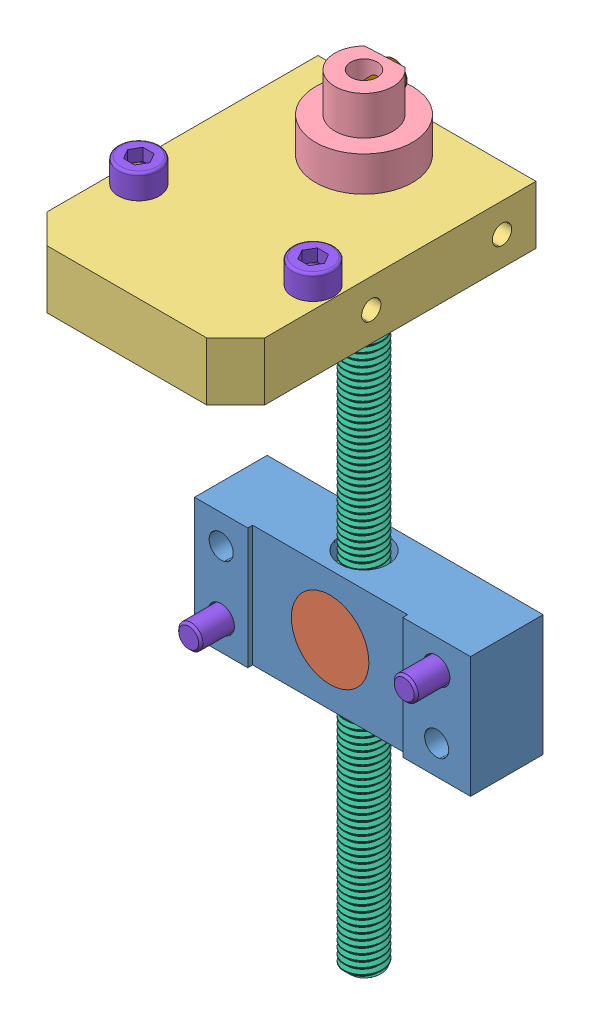
SolidWorks assembly S5 - thanh_phan, configuration Default. Lengths in mm.
Overall size (57 160.05 62).
12 component instances, 9 part files, 24 mates.
Components (placement in the parent):
- thanh ngang-5: thanh ngang [Default] at (73.0889 155.42 65.6963) x (-1 0 0) z (0 1 0) size (57 15 25)
- dai oc-1: dai oc [Default] at (71.5889 158.42 65.6963) x (0 1 0) z (1 0 0) size (16 14 16)
- tam de nho-4: tam de nho [Default] at (71.5889 241.6685 90.6963) x (1 0 0) z (0 0 -1) size (45 12 62)
- dau kep truc vit-2: dau kep truc vit [Default] at (71.5889 256.8685 72.6963) x (-0.045414 0 -0.998968) z (-0.998968 0 0.045414) size (20 25 20)
- vong_dem-2: vong_dem [Default] at (71.5889 229.8685 72.6963) x (0.969315 0 0.245821) z (-0.245821 0 0.969315) size (19.6 2 19.6)
- vit me M8x150mm-2: vit me M8x150mm [Default] at (71.5889 171.8685 72.6963) x (0.826851 0 0.562421) z (0 1 0) size (10.85 10.06 150.11)
- hex nut gradec_din-2: hex nut gradec_din [Hexagon Nut ISO 4034 - M8 - N] at (71.5889 221.9685 72.6963) x (-0.899635 0 -0.436642) z (0 -1 0) size (13 15.01 7.9)
- socket head cap screw_din-3: socket head cap screw_din [DIN 912 M5 x 16 --- 16N] at (50.0889 151.92 66.3963) x (0 0 1) z (-1 0 0) size (21 8.5 8.5)
- socket head cap screw_din-4: socket head cap screw_din [DIN 912 M5 x 16 --- 16N] at (94.5889 164.92 66.3963) x (0 0 1) z (-1 0 0) size (21 8.5 8.5)
- socket head cap screw_din-15: socket head cap screw_din [DIN 912 M5 x 12 --- 12N] at (53.5889 246.6685 101.1963) x (0 -1 0) z (0 0 1) size (17 8.5 8.5)
- socket head cap screw_din-16: socket head cap screw_din [DIN 912 M5 x 12 --- 12N] at (89.5889 246.6685 101.1963) x (0 -1 0) z (0 0 1) size (17 8.5 8.5)
- socket head thin cap screw_din-18: socket head thin cap screw_din [DIN 7984 - M3 x 5 --- 3.5N] at (71.2937 252.8685 66.203) x (0.045414 0 0.998968) z (0.400979 0.915906 -0.018229) size (7 5.5 5.5)
Mates (geometry in assembly coordinates):
- Parallel48: parallel anti-aligned: plane of thanh ngang-5 through (73.0889 155.42 65.6963) normal (0 0 -1); plane of dai oc-1 through (80.1238 179.42 79.6963) normal (0 0 1)
- Concentric30: concentric anti-aligned: cylinder of thanh ngang-5 through (71.5889 -0.08 72.6963) axis (0 1 0) radius 5; cylinder of dai oc-1 through (71.5889 179.42 72.6963) axis (0 -1 0) radius 4
- Concentric31: concentric aligned: cylinder of thanh ngang-5 through (71.5889 158.42 236.6963) axis (0 0 -1) radius 8; cylinder of dai oc-1 through (71.5889 158.42 79.6963) axis (0 0 -1) radius 8
- Parallel55: parallel anti-aligned: plane of tam de nho-4 through (71.5889 241.6685 90.6963) normal (0 1 0); plane of dau kep truc vit-2 through (71.5889 231.8685 72.6963) normal (0 -1 0)
- Concentric33: concentric aligned: cylinder of tam de nho-4 through (71.5889 241.6685 72.6963) axis (0 -1 0) radius 7; cylinder of dau kep truc vit-2 through (71.5889 241.6685 72.6963) axis (0 -1 0) radius 7
- Coincident46: coincident anti-aligned: plane of tam de nho-4 through (71.5889 241.6685 90.6963) normal (0 1 0); plane of dau kep truc vit-2 through (71.5889 241.6685 72.6963) normal (0 -1 0)
- Concentric34: concentric aligned: cylinder of dau kep truc vit-2 through (71.5889 246.8685 72.6963) axis (0 -1 0) radius 4; cylinder of vong_dem-2 through (71.5889 231.8685 72.6963) axis (0 -1 0) radius 4.25
- Coincident47: coincident anti-aligned: plane of dau kep truc vit-2 through (71.5889 231.8685 72.6963) normal (0 -1 0); plane of vong_dem-2 through (71.5889 231.8685 72.6963) normal (0 1 0)
- Concentric35: concentric anti-aligned: cylinder of dau kep truc vit-2 through (71.5889 246.8685 72.6963) axis (0 -1 0) radius 4; cylinder of vit me M8x150mm-2 through (71.5889 171.8685 72.6963) axis (0 1 0) radius 3.933
- Coincident48: coincident anti-aligned: plane of dau kep truc vit-2 through (71.5889 246.8685 72.6963) normal (0 -1 0); plane of vit me M8x150mm-2 through (71.5889 246.8685 72.6963) normal (0 1 0)
- Concentric37: concentric anti-aligned: cylinder of vit me M8x150mm-2 through (71.5889 171.8685 72.6963) axis (0 1 0) radius 3.933; cylinder of hex nut gradec_din-2 through (71.5889 229.8685 72.6963) axis (0 -1 0) radius 3.4
- Coincident49: coincident anti-aligned: plane of vong_dem-2 through (71.5889 229.8685 72.6963) normal (0 -1 0); plane of hex nut gradec_din-2 through (74.8661 229.8685 65.944) normal (0 1 0)
- Lock1: lock: unknown of vit me M8x150mm-2; unknown of hex nut gradec_din-2
- Lock2: lock: unknown of dau kep truc vit-2; unknown of hex nut gradec_din-2
- Concentric62: concentric aligned: cylinder of thanh ngang-5 through (50.0889 151.92 71.3963) axis (0 0 -1) radius 5; cylinder of socket head cap screw_din-3 through (50.0889 151.92 34.6463) axis (0 0 -1) radius 4.25
- Coincident67: coincident anti-aligned: plane of thanh ngang-5 through (50.0889 151.92 71.3963) normal (0 0 -1); plane of socket head cap screw_din-3 through (50.0889 156.17 71.3963) normal (0 0 1)
- Concentric63: concentric aligned: cylinder of thanh ngang-5 through (94.5889 164.92 124.3963) axis (0 0 -1) radius 2.75; cylinder of socket head cap screw_din-4 through (94.5889 164.92 34.6463) axis (0 0 -1) radius 4.25
- Coincident68: coincident anti-aligned: plane of thanh ngang-5 through (94.5889 164.92 71.3963) normal (0 0 -1); plane of socket head cap screw_din-4 through (94.5889 169.17 71.3963) normal (0 0 1)
- Concentric74: concentric anti-aligned: cylinder of tam de nho-4 through (53.5889 241.6685 101.1963) axis (0 -1 0) radius 2.75; cylinder of socket head cap screw_din-15 through (53.5889 278.4185 101.1963) axis (0 1 0) radius 4.25
- Coincident79: coincident anti-aligned: plane of tam de nho-4 through (71.5889 241.6685 90.6963) normal (0 1 0); plane of socket head cap screw_din-15 through (57.8389 241.6685 101.1963) normal (0 -1 0)
- Concentric75: concentric anti-aligned: cylinder of tam de nho-4 through (89.5889 241.6685 101.1963) axis (0 -1 0) radius 2.75; cylinder of socket head cap screw_din-16 through (89.5889 278.4185 101.1963) axis (0 1 0) radius 4.25
- Coincident80: coincident anti-aligned: plane of tam de nho-4 through (71.5889 241.6685 90.6963) normal (0 1 0); plane of socket head cap screw_din-16 through (93.8389 241.6685 101.1963) normal (0 -1 0)
- Concentric90: concentric aligned: cylinder of dau kep truc vit-2 through (71.5662 252.8685 72.1968) axis (-0.045414 0 -0.998968) radius 1.5; cylinder of socket head thin cap screw_din-18 through (69.8518 252.8685 34.4858) axis (-0.045414 0 -0.998968) radius 2.75
- Coincident97: coincident anti-aligned: plane of dau kep truc vit-2 through (71.3845 240.7907 68.201) normal (-0.045414 0 -0.998968); plane of socket head thin cap screw_din-18 through (73.9007 251.7646 68.0866) normal (0.045414 0 0.998968)
